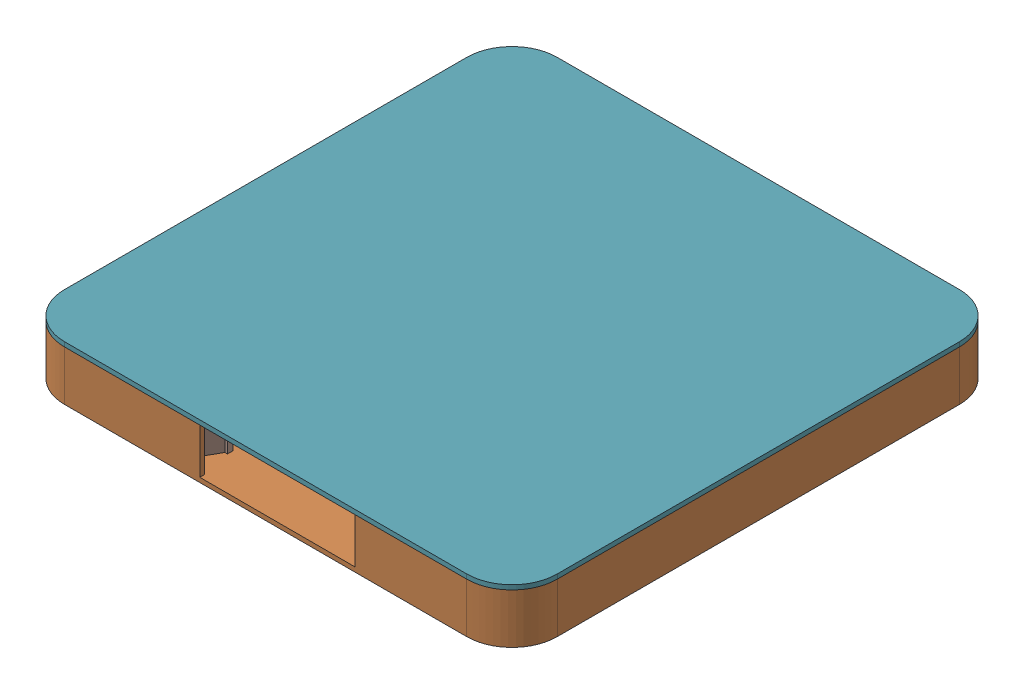
SolidWorks assembly speaker and attachment with BAE, configuration Default. Lengths in mm.
Overall size (108.8 38.35 108.8).
6 component instances, 5 part files, 2 mates.
Components (placement in the parent):
- speaker and attachment assembly-1: speaker and attachment assembly [Default] at origin size (108.8 116.34 108.8)
  - visaton ex 60 s-1: visaton ex 60 s [Default] at origin size (58 21.05 58)
  - attachment-1: attachment [Default] at (0 21.05 0) size (108.8 11 108.8)
  - lid-1: lid [Default] at (0 32.15 0) size (108.8 5 108.8)
  - honeycomb-1: honeycomb [Default] at (0 22.05 0) x (1 0 0) z (0 1 0) size (106.8 106.8 10)
- visaton ex 60 s BASE-1: visaton ex 60 s BASE [Default] at origin size (58 26.35 58)
Mates (geometry in assembly coordinates):
- Distance1: distance = 0.3 mm anti-aligned: plane of speaker and attachment assembly-1/visaton ex 60 s-1 through (0 0 0) normal (0 -1 0); plane of visaton ex 60 s BASE-1 through (0 -0.3 0) normal (0 1 0)
- Concentric2: concentric aligned: circle of speaker and attachment assembly-1/visaton ex 60 s-1; circle of visaton ex 60 s BASE-1
